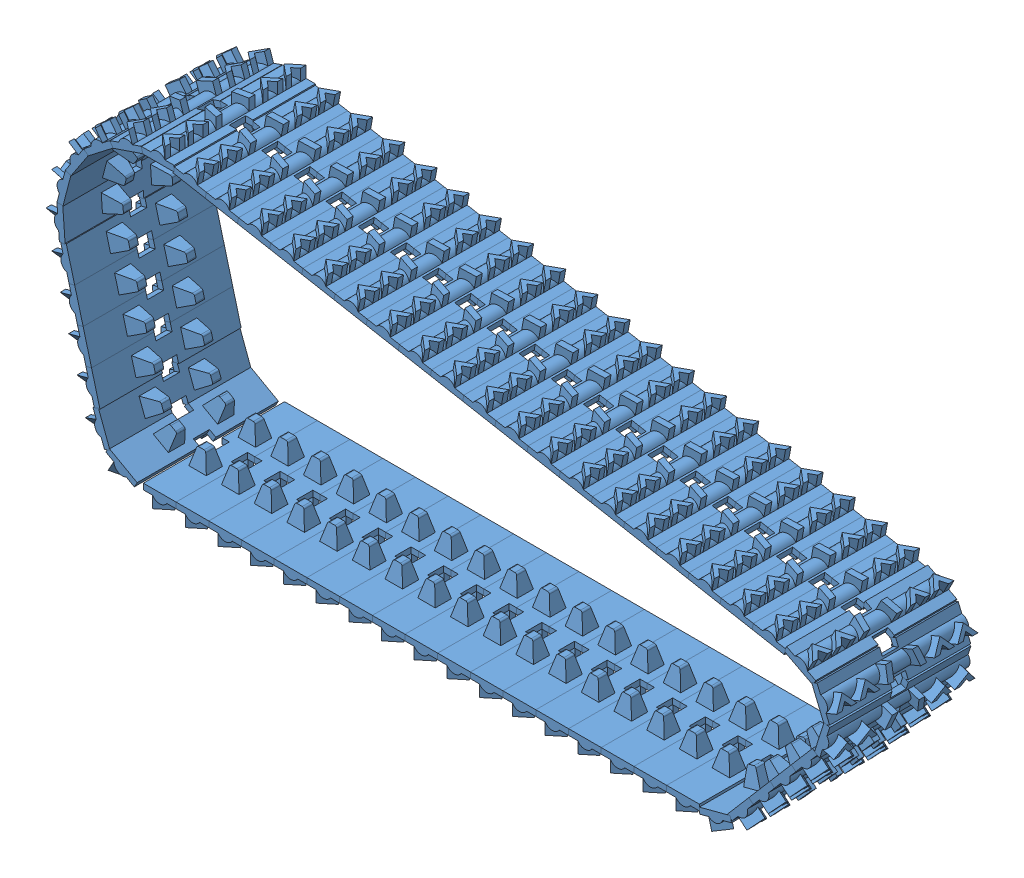
SolidWorks assembly Гусеница Z56, configuration 00. Lengths in mm.
Overall size (1228.15 497.21 218.02).
56 component instances, 1 part files, 3 mates.
Components (placement in the parent):
- Трак гусеницы-1: Трак гусеницы [По умолчанию] at (89.75 -9 0) x (0 0 -1) z (-1 0 0) size (218.02 54 50.5)
- Трак гусеницы-2: Трак гусеницы [По умолчанию] at (140.25 -9 0) x (0 0 -1) z (-1 0 0) size (218.02 54 50.5)
- Трак гусеницы-3: Трак гусеницы [По умолчанию] at (190.75 -9 0) x (0 0 -1) z (-1 0 0) size (218.02 54 50.5)
- Трак гусеницы-4: Трак гусеницы [По умолчанию] at (241.25 -9 0) x (0 0 -1) z (-1 0 0) size (218.02 54 50.5)
- Трак гусеницы-5: Трак гусеницы [По умолчанию] at (291.75 -9 0) x (0 0 -1) z (-1 0 0) size (218.02 54 50.5)
- Трак гусеницы-6: Трак гусеницы [По умолчанию] at (342.25 -9 0) x (0 0 -1) z (-1 0 0) size (218.02 54 50.5)
- Трак гусеницы-7: Трак гусеницы [По умолчанию] at (392.75 -9 0) x (0 0 -1) z (-1 0 0) size (218.02 54 50.5)
- Трак гусеницы-8: Трак гусеницы [По умолчанию] at (443.25 -9 0) x (0 0 -1) z (-1 0 0) size (218.02 54 50.5)
- Трак гусеницы-9: Трак гусеницы [По умолчанию] at (493.75 -9 0) x (0 0 -1) z (-1 0 0) size (218.02 54 50.5)
- Трак гусеницы-10: Трак гусеницы [По умолчанию] at (544.25 -9 0) x (0 0 -1) z (-1 0 0) size (218.02 54 50.5)
- Трак гусеницы-11: Трак гусеницы [По умолчанию] at (594.75 -9 0) x (0 0 -1) z (-1 0 0) size (218.02 54 50.5)
- Трак гусеницы-12: Трак гусеницы [По умолчанию] at (645.25 -9 0) x (0 0 -1) z (-1 0 0) size (218.02 54 50.5)
- Трак гусеницы-13: Трак гусеницы [По умолчанию] at (695.75 -9 0) x (0 0 -1) z (-1 0 0) size (218.02 54 50.5)
- Трак гусеницы-14: Трак гусеницы [По умолчанию] at (746.25 -9 0) x (0 0 -1) z (-1 0 0) size (218.02 54 50.5)
- Трак гусеницы-15: Трак гусеницы [По умолчанию] at (796.7501 -9 0) x (0 0 -1) z (-1 0 0) size (218.02 54 50.5)
- Трак гусеницы-16: Трак гусеницы [По умолчанию] at (847.2501 -9 0) x (0 0 -1) z (-1 0 0) size (218.02 54 50.5)
- Трак гусеницы-17: Трак гусеницы [По умолчанию] at (897.7501 -9 0) x (0 0 -1) z (-1 0 0) size (218.02 54 50.5)
- Трак гусеницы-18: Трак гусеницы [По умолчанию] at (948.192 -6.5782 0) x (0 0 -1) z (-0.967051 -0.254583 0) size (218.02 54 50.5)
- Трак гусеницы-19: Трак гусеницы [По умолчанию] at (989.8366 21.987 0) x (0 0 -1) z (-0.650039 -0.759901 0) size (218.02 54 50.5)
- Трак гусеницы-20: Трак гусеницы [По умолчанию] at (1022.6636 60.362 0) x (0 0 -1) z (-0.650039 -0.759901 0) size (218.02 54 50.5)
- Трак гусеницы-21: Трак гусеницы [По умолчанию] at (1055.4906 98.737 0) x (0 0 -1) z (-0.650039 -0.759901 0) size (218.02 54 50.5)
- Трак гусеницы-22: Трак гусеницы [По умолчанию] at (1088.3176 137.112 0) x (0 0 -1) z (-0.650039 -0.759901 0) size (218.02 54 50.5)
- Трак гусеницы-23: Трак гусеницы [По умолчанию] at (1116.524 179.0005 0) x (0 0 -1) z (-0.303039 -0.952978 0) size (218.02 54 50.5)
- Трак гусеницы-24: Трак гусеницы [По умолчанию] at (1114.3632 229.4542 0) x (0 0 -1) z (0.383407 -0.92358 0) size (218.02 54 50.5)
- Трак гусеницы-25: Трак гусеницы [По умолчанию] at (1080.1567 266.6048 0) x (0 0 -1) z (0.888857 -0.458185 0) size (218.02 54 50.5)
- Трак гусеницы-26: Трак гусеницы [По умолчанию] at (1031.1494 278.7921 0) x (0 0 -1) z (0.983712 -0.17975 0) size (218.02 54 50.5)
- Трак гусеницы-27: Трак гусеницы [По умолчанию] at (981.4719 287.8695 0) x (0 0 -1) z (0.983712 -0.17975 0) size (218.02 54 50.5)
- Трак гусеницы-28: Трак гусеницы [По умолчанию] at (931.7944 296.9468 0) x (0 0 -1) z (0.983712 -0.17975 0) size (218.02 54 50.5)
- Трак гусеницы-29: Трак гусеницы [По умолчанию] at (882.1169 306.0242 0) x (0 0 -1) z (0.983712 -0.17975 0) size (218.02 54 50.5)
- Трак гусеницы-30: Трак гусеницы [По умолчанию] at (832.4394 315.1015 0) x (0 0 -1) z (0.983712 -0.17975 0) size (218.02 54 50.5)
- Трак гусеницы-31: Трак гусеницы [По умолчанию] at (782.762 324.1789 0) x (0 0 -1) z (0.983712 -0.17975 0) size (218.02 54 50.5)
- Трак гусеницы-32: Трак гусеницы [По умолчанию] at (733.0845 333.2563 0) x (0 0 -1) z (0.983712 -0.17975 0) size (218.02 54 50.5)
- Трак гусеницы-33: Трак гусеницы [По умолчанию] at (683.407 342.3336 0) x (0 0 -1) z (0.983712 -0.17975 0) size (218.02 54 50.5)
- Трак гусеницы-34: Трак гусеницы [По умолчанию] at (633.7295 351.411 0) x (0 0 -1) z (0.983712 -0.17975 0) size (218.02 54 50.5)
- Трак гусеницы-35: Трак гусеницы [По умолчанию] at (584.052 360.4883 0) x (0 0 -1) z (0.983712 -0.17975 0) size (218.02 54 50.5)
- Трак гусеницы-36: Трак гусеницы [По умолчанию] at (534.3746 369.5657 0) x (0 0 -1) z (0.983712 -0.17975 0) size (218.02 54 50.5)
- Трак гусеницы-37: Трак гусеницы [По умолчанию] at (484.6971 378.6431 0) x (0 0 -1) z (0.983712 -0.17975 0) size (218.02 54 50.5)
- Трак гусеницы-38: Трак гусеницы [По умолчанию] at (435.0196 387.7204 0) x (0 0 -1) z (0.983712 -0.17975 0) size (218.02 54 50.5)
- Трак гусеницы-39: Трак гусеницы [По умолчанию] at (385.3421 396.7978 0) x (0 0 -1) z (0.983712 -0.17975 0) size (218.02 54 50.5)
- Трак гусеницы-40: Трак гусеницы [По умолчанию] at (335.6647 405.8751 0) x (0 0 -1) z (0.983712 -0.17975 0) size (218.02 54 50.5)
- Трак гусеницы-41: Трак гусеницы [По умолчанию] at (285.9872 414.9525 0) x (0 0 -1) z (0.983712 -0.17975 0) size (218.02 54 50.5)
- Трак гусеницы-42: Трак гусеницы [По умолчанию] at (236.3097 424.0299 0) x (0 0 -1) z (0.983712 -0.17975 0) size (218.02 54 50.5)
- Трак гусеницы-43: Трак гусеницы [По умолчанию] at (186.6322 433.1072 0) x (0 0 -1) z (0.983712 -0.17975 0) size (218.02 54 50.5)
- Трак гусеницы-44: Трак гусеницы [По умолчанию] at (136.9547 442.1846 0) x (0 0 -1) z (0.983712 -0.17975 0) size (218.02 54 50.5)
- Трак гусеницы-45: Трак гусеницы [По умолчанию] at (86.8881 448.7866 0) x (0 0 -1) z (1 -0.000289 0) size (218.02 54 50.5)
- Трак гусеницы-46: Трак гусеницы [По умолчанию] at (37.0666 440.5364 0) x (0 0 -1) z (0.946527 0.322626 0) size (218.02 54 50.5)
- Трак гусеницы-47: Трак гусеницы [По умолчанию] at (-7.4221 416.6407 0) x (0 0 -1) z (0.791648 0.610977 0) size (218.02 54 50.5)
- Трак гусеницы-48: Трак гусеницы [По умолчанию] at (-41.8118 379.6597 0) x (0 0 -1) z (0.551958 0.833872 0) size (218.02 54 50.5)
- Трак гусеницы-49: Трак гусеницы [По умолчанию] at (-62.4182 333.5552 0) x (0 0 -1) z (0.253134 0.967431 0) size (218.02 54 50.5)
- Трак гусеницы-50: Трак гусеницы [По умолчанию] at (-67.0336 283.2665 0) x (0 0 -1) z (-0.072809 0.997346 0) size (218.02 54 50.5)
- Трак гусеницы-51: Трак гусеницы [По умолчанию] at (-56.666 233.8422 0) x (0 0 -1) z (-0.257373 0.966312 0) size (218.02 54 50.5)
- Трак гусеницы-52: Трак гусеницы [По умолчанию] at (-43.6686 185.0434 0) x (0 0 -1) z (-0.257373 0.966312 0) size (218.02 54 50.5)
- Трак гусеницы-53: Трак гусеницы [По умолчанию] at (-30.6713 136.2447 0) x (0 0 -1) z (-0.257373 0.966312 0) size (218.02 54 50.5)
- Трак гусеницы-54: Трак гусеницы [По умолчанию] at (-17.6739 87.4459 0) x (0 0 -1) z (-0.257373 0.966312 0) size (218.02 54 50.5)
- Трак гусеницы-55: Трак гусеницы [По умолчанию] at (-4.3375 38.7387 0) x (0 0 -1) z (-0.350494 0.936565 0) size (218.02 54 50.5)
- Трак гусеницы-56: Трак гусеницы [По умолчанию] at (28.5333 0.4013 0) x (0 0 -1) z (-0.872091 0.489343 0) size (218.02 54 50.5)
Mates (geometry in assembly coordinates):
- Совпадение1: coincident: plane of Трак гусеницы-1 through (64.5 0 -109) normal (0 1 0); line of assembly
- Совпадение2: coincident: plane of Трак гусеницы-1 through (89.75 -9 0) normal (0 0 1); line of assembly
- Совпадение4: coincident: plane of Трак гусеницы-1 through (64.5 -9 -109) normal (-1 0 0); point of assembly
